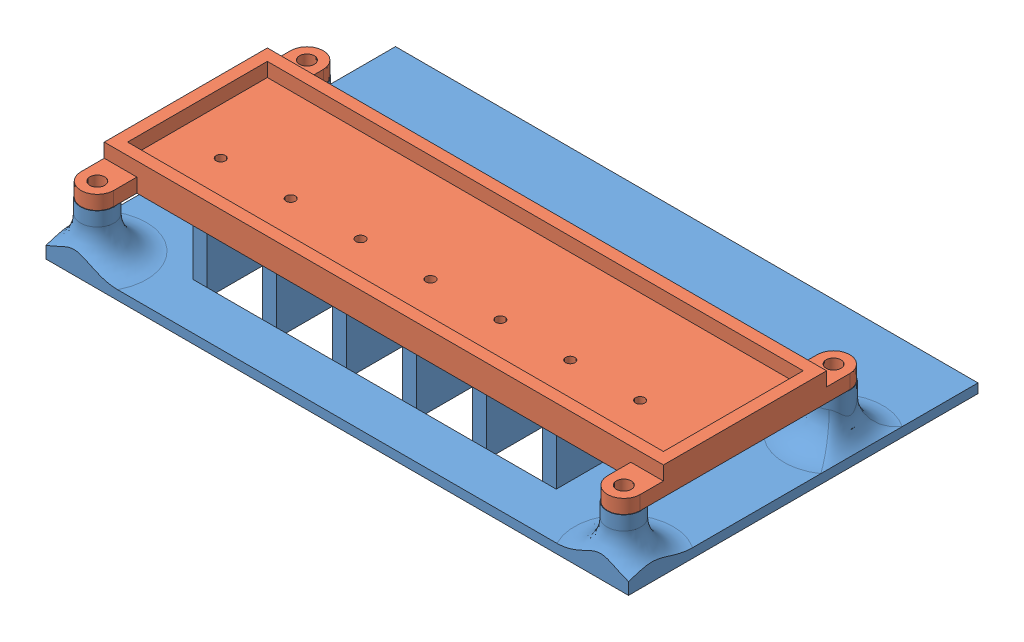
SolidWorks assembly Assem1, configuration Default. Lengths in mm.
Overall size (125 18 75).
2 component instances, 2 part files, 3 mates.
Components (placement in the parent):
- v1-base-mount-1: v1-base-mount [Default] at origin size (125 12 75)
- v1-base-1: v1-base [Default] at (-57.5 12 25) size (120 6 52)
Mates (geometry in assembly coordinates):
- Coincident1: coincident: plane of v1-base-mount-1 through (-56.5 12 32.5) normal (0 1 0); plane of v1-base-1 through (-57.5 12 25) normal (0 -1 0)
- Concentric1: concentric: cylinder of v1-base-mount-1 through (-56.5 12 32.5) axis (0 -1 0) radius 1.6; cylinder of v1-base-1 through (-56.5 15 32.5) axis (0 -1 0) radius 1.6
- Concentric2: concentric: cylinder of v1-base-mount-1 through (-56.5 12 -12.5) axis (0 -1 0) radius 1.6; cylinder of v1-base-1 through (-56.5 15 -12.5) axis (0 -1 0) radius 1.6
